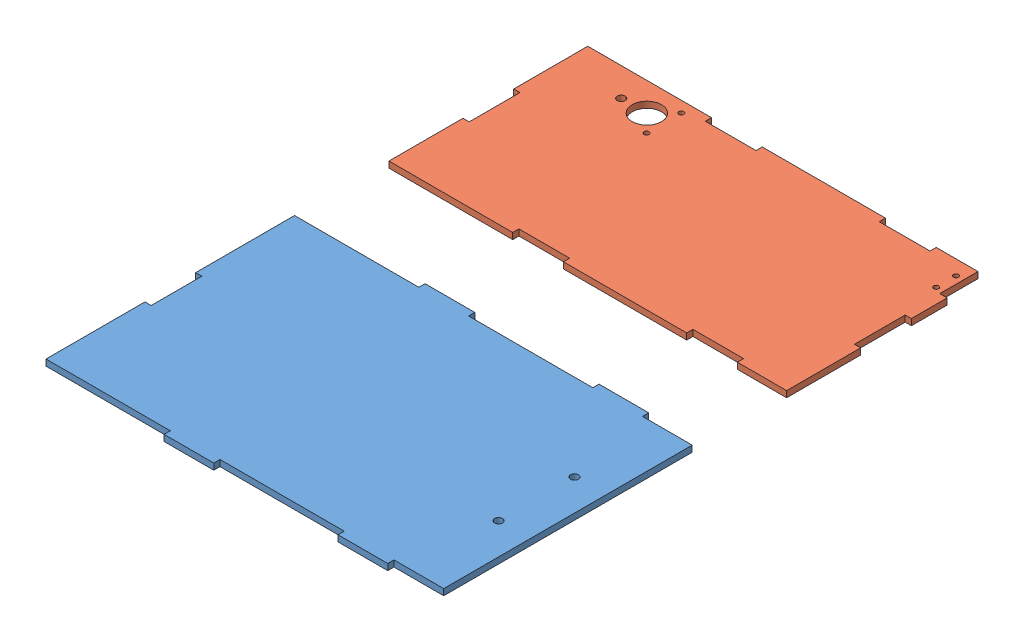
SolidWorks assembly Sheet 1, configuration Default. Lengths in mm.
Overall size (210 3.17 280).
2 component instances, 2 part files, 3 mates.
Components (placement in the parent):
- Bottom-1: Bottom [Default] at (24.4969 97.1911 177.1449) size (203.2 3.17 133.35)
- Long Side-1: Long Side [Default] at (40.5829 97.1911 2.6884) size (203.2 3.17 101.6)
Mates (geometry in assembly coordinates):
- Coincident2: coincident: line of Long Side-1 through (28.5048 100.3661 -47.6737) axis (-1 0 0); line of assembly
- Coincident4: coincident: line of Long Side-1 through (-34.7412 100.3661 16.0803) axis (0 0 1); line of assembly
- Symmetric1: symmetric: plane of Bottom-1 through (24.4969 97.1911 177.1449) normal (0 -1 0); plane of Long Side-1 through (40.5829 97.1911 2.6884) normal (0 -1 0); plane of Bottom-1 through (24.4969 97.1911 177.1449) normal (0 1 0)
